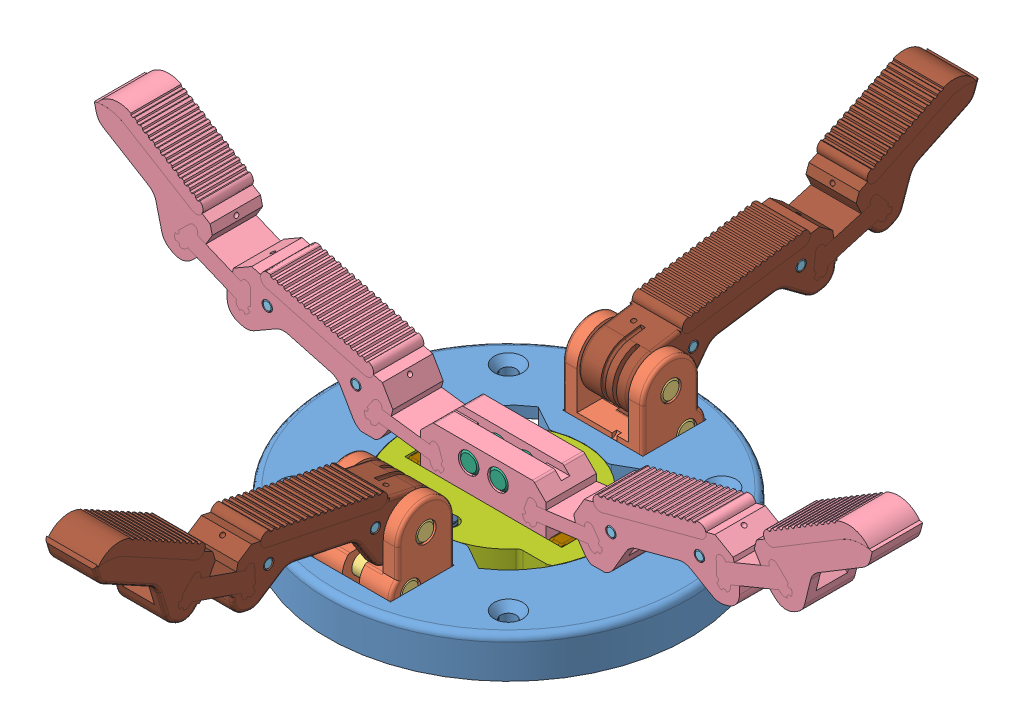
SolidWorks assembly asm_upper_hand, configuration Default. Lengths in mm.
Overall size (247.99 72.36 290.7).
28 component instances, 11 part files, 47 mates.
Components (placement in the parent):
- top_outer-1: top_outer [Default] at (34.5547 64.3421 89.7406) size (115 12.78 115)
- finger_base_pf-1: finger_base_pf [Default] at (4.6376 22.7271 -88.248) size (33.5 28.98 20.18)
  - pivot_base-1: pivot_base [Default] at (29.9046 41.615 134.046) x (-1 0 0) z (0 0 -1) size (33.5 28.98 20.18)
  - 98381A542 D1-4 L1-1: 98381A542 D1-4 L1 [98381A542] at (29.9546 61.59 138.9886) size (25.4 6.35 6.35)
  - 98381A542 D1-4 L1-2: 98381A542 D1-4 L1 [98381A542] at (29.9546 47.8525 134.046) size (25.4 6.35 6.35)
- finger_base_pf-2: finger_base_pf [Default] at (64.4468 22.7271 267.7291) x (-1 0 0) z (0 0 -1) size (33.5 28.98 20.18)
  - pivot_base-1: pivot_base [Default] at (29.9046 41.615 134.046) x (-1 0 0) z (0 0 -1) size (33.5 28.98 20.18)
  - 98381A542 D1-4 L1-1: 98381A542 D1-4 L1 [98381A542] at (29.9546 61.59 138.9886) size (25.4 6.35 6.35)
  - 98381A542 D1-4 L1-2: 98381A542 D1-4 L1 [98381A542] at (29.9546 47.8525 134.046) size (25.4 6.35 6.35)
- q_ffff-1: q_ffff [Default] at (44.5547 76.3421 89.7516) x (-0.001108 0 0.999999) z (-0.999999 0 -0.001108) size (24 58.4 247.96)
- 98381A472 D1-8 L5-8-1: 98381A472 D1-8 L5-8 [98381A472] at (75.1996 82.7614 89.8481) x (-0.001108 0 0.999999) z (-0.999999 0 -0.001108) size (15.88 3.17 3.17)
- 98381A539 D1-4 L5-8-1: 98381A539 D1-4 L5-8 [98381A539] at (29.8796 79.1671 89.7979) x (-0.001108 0 0.999999) z (-0.999999 0 -0.001108) size (15.88 6.35 6.35)
- 98381A472 D1-8 L5-8-2: 98381A472 D1-8 L5-8 [98381A472] at (-34.3036 90.3211 89.7268) x (-0.001108 0 0.999999) z (-0.999999 0 -0.001108) size (15.88 3.17 3.17)
- 98381A472 D1-8 L5-8-3: 98381A472 D1-8 L5-8 [98381A472] at (-6.0903 82.7614 89.758) x (-0.001108 0 0.999999) z (-0.999999 0 -0.001108) size (15.88 3.17 3.17)
- 98381A472 D1-8 L5-8-4: 98381A472 D1-8 L5-8 [98381A472] at (103.4129 90.3211 89.8793) x (-0.001108 0 0.999999) z (-0.999999 0 -0.001108) size (15.88 3.17 3.17)
- 98381A539 D1-4 L5-8-2: 98381A539 D1-4 L5-8 [98381A539] at (39.2296 79.1671 89.8082) x (-0.001108 0 0.999999) z (-0.999999 0 -0.001108) size (15.88 6.35 6.35)
- top_inner-1: top_inner [Default] at (34.5547 64.3421 89.7406) x (0.999999 0 0.001108) z (-0.001108 0 0.999999) size (72 6.4 48)
- 93365A130 6-32 insert-1: 93365A130 6-32 insert [Default] at (34.5752 68.1521 71.2406) x (1 0 0) z (0 -1 0) size (5.23 5.23 3.81)
- 93365A130 6-32 insert-2: 93365A130 6-32 insert [Default] at (34.5342 68.1521 108.2406) x (1 0 0) z (0 -1 0) size (5.23 5.23 3.81)
- gear_main-1: gear_main [Default] at (34.5547 61.0921 89.7406) x (-0.999999 0 -0.001108) z (0 -1 0) size (59.97 59.97 15.65)
- 92196A146 6-32 L3-8  socket-1: 92196A146 6-32 L3-8  socket [Default] at (34.5342 58.3421 108.2406) x (1 0 0) z (0 1 0) size (5.74 5.74 13.34)
- 92196A146 6-32 L3-8  socket-3: 92196A146 6-32 L3-8  socket [Default] at (34.5752 58.3421 71.2406) x (1 0 0) z (0 1 0) size (5.74 5.74 13.34)
- q_pf-1: q_pf [Default] at (34.6922 84.3171 50.7406) x (1 0 0) z (0 -0.14871 0.988881) size (16.19 30.86 115.48)
- 98381A472 D1-8 L5-8-5: 98381A472 D1-8 L5-8 [98381A472] at (34.7547 88.2661 39.0225) size (15.88 3.17 3.17)
- 98381A472 D1-8 L5-8-6: 98381A472 D1-8 L5-8 [98381A472] at (34.7547 93.4305 4.6806) size (15.88 3.17 3.17)
- 98381A472 D1-8 L5-8-7: 98381A472 D1-8 L5-8 [98381A472] at (34.6297 96.0106 174.214) x (-1 0 0) z (0 0 -1) size (15.88 3.17 3.17)
- q_pf-2: q_pf [Default] at (34.6922 84.3171 128.7406) x (-1 0 0) z (0 -0.204177 -0.978934) size (16.19 30.86 115.48)
- 98381A472 D1-8 L5-8-8: 98381A472 D1-8 L5-8 [98381A472] at (34.6297 88.9199 140.2176) x (-1 0 0) z (0 0 -1) size (15.88 3.17 3.17)
Mates (geometry in assembly coordinates):
- Coincident3: coincident: plane of top_outer-1 through (34.5547 67.3421 89.7406) normal (0 -1 0); plane of finger_base_pf-1/pivot_base-1 through (34.5422 67.3421 45.798) normal (0 1 0)
- Coincident4: coincident: plane of top_outer-1 through (17.7922 67.3421 39.4456) normal (1 0 0); plane of finger_base_pf-1/pivot_base-1 through (17.7922 67.3421 39.5605) normal (-1 0 0)
- Coincident5: coincident: plane of top_outer-1 through (21.7922 64.3421 59.7406) normal (0 0 -1); plane of finger_base_pf-1/pivot_base-1 through (21.7922 84.3171 59.7406) normal (0 0 1)
- Coincident7: coincident: plane of top_outer-1 through (21.7922 64.3421 119.7406) normal (0 0 1); plane of finger_base_pf-2/pivot_base-1 through (47.2922 84.3171 119.7406) normal (0 0 -1)
- Coincident8: coincident: plane of top_outer-1 through (34.5547 67.3421 89.7406) normal (0 -1 0); plane of finger_base_pf-2/pivot_base-1 through (34.5422 67.3421 133.6832) normal (0 1 0)
- Coincident9: coincident: plane of top_outer-1 through (17.7922 67.3421 140.0356) normal (1 0 0); plane of finger_base_pf-2/pivot_base-1 through (17.7922 67.3421 139.9207) normal (-1 0 0)
- Concentric3: concentric: cylinder of q_ffff-1 through (29.8886 79.1671 81.7351) axis (-0.001108 0 0.999999) radius 3.3; circle of 98381A539 D1-4 L5-8-1
- Concentric4: concentric: cylinder of q_ffff-1 through (39.2386 79.1671 81.7455) axis (-0.001108 0 0.999999) radius 3.3; cylinder of 98381A539 D1-4 L5-8-2 through (39.2384 79.1671 81.8707) axis (-0.001108 0 0.999999) radius 3.175
- Concentric6: concentric: cylinder of q_ffff-1 through (75.2085 82.7614 81.7853) axis (-0.001108 0 0.999999) radius 1.65; cylinder of 98381A472 D1-8 L5-8-1 through (75.2084 82.7614 81.9106) axis (-0.001108 0 0.999999) radius 1.5875
- Concentric7: concentric: cylinder of q_ffff-1 through (103.4218 90.3211 81.8166) axis (-0.001108 0 0.999999) radius 1.65; cylinder of 98381A472 D1-8 L5-8-4 through (103.4217 90.3211 81.9418) axis (-0.001108 0 0.999999) radius 1.5875
- Concentric8: concentric: cylinder of q_ffff-1 through (-6.0813 82.7614 81.6953) axis (-0.001108 0 0.999999) radius 1.65; cylinder of 98381A472 D1-8 L5-8-3 through (-6.0815 82.7614 81.8206) axis (-0.001108 0 0.999999) radius 1.5875
- Concentric9: concentric: cylinder of q_ffff-1 through (-34.2947 90.3211 81.664) axis (-0.001108 0 0.999999) radius 1.65; cylinder of 98381A472 D1-8 L5-8-2 through (-34.2948 90.3211 81.7893) axis (-0.001108 0 0.999999) radius 1.5875
- Coincident11: coincident: plane of 98381A472 D1-8 L5-8-2 through (-34.3124 90.3211 97.6643) normal (-0.001108 0 0.999999); plane of 98381A472 D1-8 L5-8-3 through (-6.0991 82.7614 97.6955) normal (-0.001108 0 0.999999)
- Coincident12: coincident: plane of 98381A539 D1-4 L5-8-1 through (29.8709 79.1671 97.7354) normal (-0.001108 0 0.999999); plane of 98381A472 D1-8 L5-8-3 through (-6.0991 82.7614 97.6955) normal (-0.001108 0 0.999999)
- Coincident13: coincident: plane of 98381A539 D1-4 L5-8-1 through (29.8709 79.1671 97.7354) normal (-0.001108 0 0.999999); plane of 98381A539 D1-4 L5-8-2 through (39.2208 79.1671 97.7457) normal (-0.001108 0 0.999999)
- Coincident14: coincident: plane of 98381A472 D1-8 L5-8-4 through (103.4041 90.3211 97.8168) normal (-0.001108 0 0.999999); plane of 98381A539 D1-4 L5-8-2 through (39.2208 79.1671 97.7457) normal (-0.001108 0 0.999999)
- Coincident15: coincident: plane of 98381A472 D1-8 L5-8-1 through (75.1908 82.7614 97.7856) normal (-0.001108 0 0.999999); plane of 98381A539 D1-4 L5-8-2 through (39.2208 79.1671 97.7457) normal (-0.001108 0 0.999999)
- Coincident16: coincident: plane of q_ffff-1 through (34.5459 85.3421 97.7406) normal (-0.001108 0 0.999999); plane of 98381A472 D1-8 L5-8-1 through (75.1908 82.7614 97.7856) normal (-0.001108 0 0.999999)
- Concentric10: concentric: circle of top_inner-1; circle of 93365A130 6-32 insert-2
- Concentric11: concentric: cylinder of top_inner-1 through (34.5752 64.3421 71.2406) axis (0 1 0) radius 2.5; circle of 93365A130 6-32 insert-1
- Coincident17: coincident: plane of top_inner-1 through (34.5547 64.3421 89.7406) normal (0 -1 0); plane of 93365A130 6-32 insert-1 through (34.5752 64.3421 71.2406) normal (0 -1 0)
- Coincident19: coincident: plane of top_inner-1 through (34.5547 64.3421 89.7406) normal (0 -1 0); plane of 93365A130 6-32 insert-2 through (34.5342 64.3421 108.2406) normal (0 -1 0)
- Coincident20: coincident: plane of q_ffff-1 through (44.5547 67.3421 89.7516) normal (0 1 0); plane of top_inner-1 through (34.5547 67.3421 89.7406) normal (0 -1 0)
- Coincident21: coincident: plane of q_ffff-1 through (34.5414 67.3421 101.7406) normal (-0.001108 0 0.999999); plane of top_inner-1 through (14.5414 67.3421 101.7184) normal (0.001108 0 -0.999999)
- Coincident23: coincident: plane of q_ffff-1 through (54.5547 76.3421 89.7627) normal (0.999999 0 0.001108); plane of top_inner-1 through (54.5636 70.7421 81.7627) normal (-0.999999 0 -0.001108)
- Coincident24: coincident: plane of top_outer-1 through (34.5547 67.3421 89.7406) normal (0 -1 0); plane of top_inner-1 through (34.5547 67.3421 89.7406) normal (0 1 0)
- Concentric15: concentric: cylinder of top_outer-1 through (34.5547 29.034 89.7406) axis (0 1 0) radius 24.15; cylinder of top_inner-1 through (34.5547 70.7421 89.7406) axis (0 -1 0) radius 32
- Coincident26: coincident: plane of top_inner-1 through (34.5547 64.3421 89.7406) normal (0 -1 0); plane of gear_main-1 through (34.5547 64.3421 89.7406) normal (0 1 0)
- Coincident27: coincident: plane of top_inner-1 through (9.5459 70.7421 97.7129) normal (0.999999 0 0.001108); plane of gear_main-1 through (9.5459 70.7421 97.7129) normal (-0.999999 0 -0.001108)
- Concentric16: concentric: circle of 93365A130 6-32 insert-2; cylinder of gear_main-1 through (34.5342 63.8421 108.2406) axis (0 -1 0) radius 1.85
- Coincident31: coincident: plane of gear_main-1 through (34.5547 58.3421 89.7406) normal (0 -1 0); plane of 92196A146 6-32 L3-8  socket-1 through (34.5342 58.3421 108.2406) normal (0 -1 0)
- Concentric20: concentric: circle of gear_main-1; circle of 92196A146 6-32 L3-8  socket-1
- Concentric21: concentric: circle of gear_main-1; circle of 92196A146 6-32 L3-8  socket-3
- Coincident32: coincident: plane of gear_main-1 through (34.5547 58.3421 89.7406) normal (0 -1 0); circle of 92196A146 6-32 L3-8  socket-3
- Coincident33: coincident: plane of q_pf-1 through (42.6922 84.3171 50.7406) normal (1 0 0); plane of 98381A472 D1-8 L5-8-5 through (42.6922 88.2661 39.0225) normal (1 0 0)
- Concentric22: concentric: circle of q_pf-1; circle of 98381A472 D1-8 L5-8-5
- Concentric23: concentric: cylinder of q_pf-1 through (26.6922 93.4305 4.6806) axis (1 0 0) radius 1.65; circle of 98381A472 D1-8 L5-8-6
- Coincident34: coincident: plane of q_pf-1 through (42.6922 84.3171 50.7406) normal (1 0 0); plane of 98381A472 D1-8 L5-8-6 through (42.6922 93.4305 4.6806) normal (1 0 0)
- Concentric24: concentric: circle of 98381A472 D1-8 L5-8-7; cylinder of q_pf-2 through (42.6922 96.0106 174.214) axis (-1 0 0) radius 1.65
- Concentric25: concentric: circle of q_pf-2; circle of 98381A472 D1-8 L5-8-8
- Coincident35: coincident: plane of q_pf-2 through (26.6922 84.3171 128.7406) normal (-1 0 0); plane of 98381A472 D1-8 L5-8-8 through (26.6922 88.9199 140.2176) normal (-1 0 0)
- Coincident36: coincident: plane of 98381A472 D1-8 L5-8-7 through (26.6922 96.0106 174.214) normal (-1 0 0); plane of q_pf-2 through (26.6922 84.3171 128.7406) normal (-1 0 0)
- Concentric26: concentric: circle of finger_base_pf-1/pivot_base-1; circle of q_pf-1
- Coincident37: coincident: plane of finger_base_pf-1/pivot_base-1 through (42.6922 70.5796 45.798) normal (-1 0 0); plane of q_pf-1 through (42.6922 84.3171 50.7406) normal (1 0 0)
- Parallel1: parallel: plane of finger_base_pf-2/pivot_base-1 through (42.6922 70.5796 133.6832) normal (-1 0 0); plane of q_pf-2 through (42.6922 84.3171 128.7406) normal (1 0 0)
- Concentric28: concentric: circle of finger_base_pf-2/pivot_base-1; circle of q_pf-2
- Coincident40: coincident: plane of finger_base_pf-2/pivot_base-1 through (42.6922 70.5796 133.6832) normal (-1 0 0); plane of q_pf-2 through (42.6922 84.3171 128.7406) normal (1 0 0)
